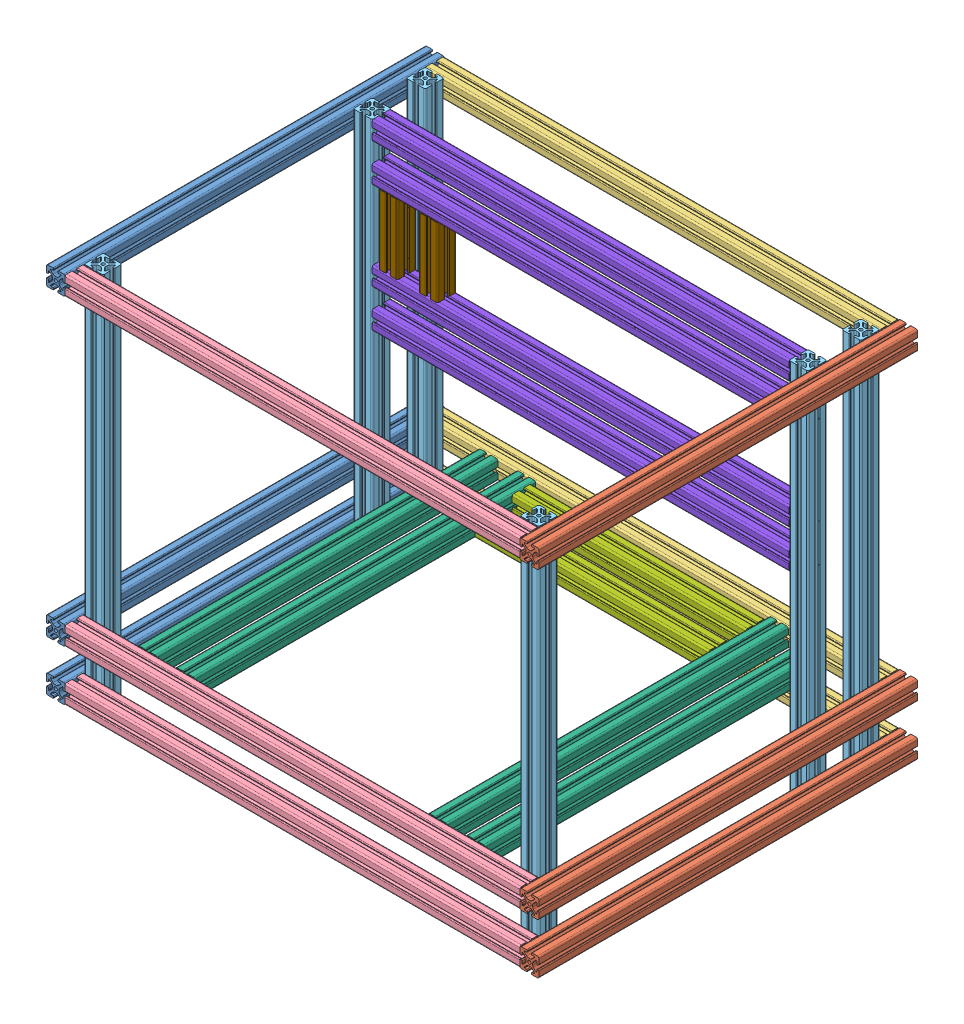
SolidWorks assembly Frame__rev6, configuration Default. Lengths in mm.
Overall size (990.6 749.3 762).
10 component instances, 10 part files, 36 mates.
Components (placement in the parent):
- Base^Frame__rev6-1: Base^Frame__rev6 [Default] at origin size (952.5 749.3 762) (hidden, virtual)
- Base_Short_Left^Frame__rev6-2: Base_Short_Left^Frame__rev6 [Default] at (0 0 381) size (38.1 749.3 762) (virtual)
- Base_Short_Right^Frame__rev6-2: Base_Short_Right^Frame__rev6 [Default] at (0 0 381) size (38.1 749.3 762) (virtual)
- Base_Long_Back^Frame__rev6-2: Base_Long_Back^Frame__rev6 [Default] at (-457.2 0 0) x (0 0 -1) z (1 0 0) size (38.1 749.3 914.4) (virtual)
- Base_Long_Front^Frame__rev6-2: Base_Long_Front^Frame__rev6 [Default] at (-457.2 0 0) x (0 0 -1) z (1 0 0) size (38.1 749.3 914.4) (virtual)
- Pillars^Frame__rev6-1: Pillars^Frame__rev6 [Default] at (0 -120.65 0) x (1 0 0) z (0 1 0) size (914.4 685.8 749.3) (virtual)
- Base Horizontals^Frame__rev6-1: Base Horizontals^Frame__rev6 [Default] at (0 0 342.9) size (698.5 38.1 685.8) (virtual)
- Base Horizontals Cross^Frame__rev6-1: Base Horizontals Cross^Frame__rev6 [Default] at (-234.95 0 0) x (0 0 -1) z (1 0 0) size (113.02 38.1 469.9) (virtual)
- Rear Horizontals^Frame__rev6-2: Rear Horizontals^Frame__rev6 [Default] at (-419.1 0 0) x (0 0 -1) z (1 0 0) size (38.1 368.3 838.2) (virtual)
- Rear Horizontals Cross^Frame__rev6-1: Rear Horizontals Cross^Frame__rev6 [Default] at (0 374.65 0) x (1 0 0) z (0 1 0) size (118.75 38.1 139.7) (virtual)
Mates (geometry in assembly coordinates):
- InPlace1: in place: plane of Base^Frame__rev6-1 through (0 0 397.75) normal (0 0 1); plane of ? through (0 0 397.75) normal (0 0 1); moOrthogonalPlaneRef_w of Base^Frame__rev6-1 through (0 0 397.75) normal (0 0 1); plane of ? through (0 0 397.75) normal (0 1 0); plane of Base^Frame__rev6-1 through (0 0 397.75) normal (0 0 1); plane of ? through (0 0 397.75) normal (1 0 0); plane of Base^Frame__rev6-1 through (0 0 381) normal (0 0 1); unknown of ?
- Coincident1: coincident aligned: plane of Base^Frame__rev6-1 through (0 0 381) normal (0 0 1); plane of Base_Short_Left^Frame__rev6-2 through (0 0 381) normal (0 0 1)
- Coincident2: coincident aligned: moOrthogonalPlaneRef_w of Base^Frame__rev6-1 through (0 0 381) axis (0 1 0); plane of Base_Short_Left^Frame__rev6-2 through (0 0 381) normal (0 1 0)
- Coincident3: coincident anti-aligned: moOrthogonalPlaneRef_w of Base^Frame__rev6-1 through (0 0 381) axis (-1 0 0); plane of Base_Short_Left^Frame__rev6-2 through (0 0 381) normal (1 0 0)
- InPlace2: in place: plane of Base^Frame__rev6-1 through (0 0 207.25) normal (0 0 1); plane of ? through (0 0 207.25) normal (0 0 1); plane of Base^Frame__rev6-1 through (0 0 207.25) normal (0 0 1); plane of ? through (0 0 207.25) normal (0 1 0); plane of Base^Frame__rev6-1 through (0 0 207.25) normal (0 0 1); plane of ? through (0 0 207.25) normal (1 0 0); plane of Base^Frame__rev6-1 through (0 0 381) normal (0 0 1); unknown of ?
- Coincident4: coincident aligned: plane of Base^Frame__rev6-1; plane of Base_Short_Right^Frame__rev6-2
- Coincident5: coincident aligned: moOrthogonalPlaneRef_w of Base^Frame__rev6-1 through (0 0 381) axis (0 1 0); plane of Base_Short_Right^Frame__rev6-2 through (0 0 381) normal (0 1 0)
- Coincident6: coincident anti-aligned: moOrthogonalPlaneRef_w of Base^Frame__rev6-1 through (0 0 381) axis (-1 0 0); plane of Base_Short_Right^Frame__rev6-2 through (0 0 381) normal (1 0 0)
- InPlace4: in place: plane of Base^Frame__rev6-1 through (-438.15 0 0) normal (1 0 0); plane of ? through (-438.15 0 0) normal (1 0 0); plane of Base^Frame__rev6-1 through (-438.15 0 0) normal (1 0 0); plane of ? through (-438.15 0 0) normal (0 1 0); plane of Base^Frame__rev6-1 through (-438.15 0 0) normal (1 0 0); plane of ? through (-438.15 0 0) normal (0 0 -1); plane of Base^Frame__rev6-1 through (-457.2 0 0) normal (1 0 0); unknown of ?
- Coincident10: coincident aligned: plane of Base^Frame__rev6-1; plane of Base_Long_Back^Frame__rev6-2
- Coincident11: coincident aligned: moOrthogonalPlaneRef_w of Base^Frame__rev6-1 through (-227.975 -457.2 0) axis (0 0 1); plane of Base_Long_Back^Frame-2 through (-457.2 0 0) normal (0 1 0)
- Coincident12: coincident anti-aligned: moOrthogonalPlaneRef_w of Base^Frame__rev6-1 through (0 0 0) axis (0 1 0); plane of Base_Long_Back^Frame-2 through (-457.2 0 0) normal (0 0 -1)
- InPlace5: in place: plane of Base^Frame__rev6-1 through (-628.65 0 0) normal (1 0 0); plane of ? through (-628.65 0 0) normal (1 0 0); plane of Base^Frame__rev6-1 through (-628.65 0 0) normal (1 0 0); plane of ? through (-628.65 0 0) normal (0 1 0); plane of Base^Frame__rev6-1 through (-628.65 0 0) normal (1 0 0); plane of ? through (-628.65 0 0) normal (0 0 -1); plane of Base^Frame__rev6-1 through (-457.2 0 0) normal (1 0 0); unknown of ?
- Coincident13: coincident aligned: plane of Base^Frame__rev6-1; plane of Base_Long_Front^Frame__rev6-2
- Coincident14: coincident aligned: moOrthogonalPlaneRef_w of Base^Frame__rev6-1 through (-227.975 -457.2 0) axis (0 0 1); plane of Base_Long_Front^Frame__rev6-2 through (-457.2 0 0) normal (0 1 0)
- Coincident15: coincident anti-aligned: moOrthogonalPlaneRef_w of Base^Frame__rev6-1 through (0 0 0) axis (0 1 0); plane of Base_Long_Front^Frame__rev6-2 through (-457.2 0 0) normal (0 0 -1)
- InPlace6: in place: plane of Base^Frame__rev6-1 through (0 -120.65 0) normal (0 1 0); plane of Pillars^Frame__rev6-1 through (0 -120.65 0) normal (0 1 0); plane of Base^Frame__rev6-1 through (0 -120.65 0) normal (0 1 0); plane of Pillars^Frame__rev6-1 through (0 -120.65 0) normal (0 0 -1); plane of Base^Frame__rev6-1 through (0 -120.65 0) normal (0 1 0); plane of Pillars^Frame__rev6-1 through (0 -120.65 0) normal (1 0 0); plane of Base^Frame__rev6-1 through (0 -120.65 0) normal (0 1 0); unknown of Pillars^Frame__rev6-1
- Coincident16: coincident aligned: plane of Base^Frame__rev6-1; plane of Pillars^Frame__rev6-1
- Coincident17: coincident aligned: moOrthogonalPlaneRef_w of Base^Frame__rev6-1; plane of Pillars^Frame__rev6-1 through (0 -120.65 0) normal (0 0 -1)
- Coincident18: coincident anti-aligned: moOrthogonalPlaneRef_w of Base^Frame__rev6-1 through (-437.525 0 -120.65) axis (0 -1 0); plane of Pillars^Frame__rev6-1 through (0 -120.65 0) normal (1 0 0)
- InPlace7: in place: plane of Base^Frame__rev6-1 through (0 0 342.9) normal (0 0 1); plane of Base Horizontals^Frame__rev6-1 through (0 0 342.9) normal (0 0 1); plane of Base^Frame__rev6-1 through (0 0 342.9) normal (0 0 1); plane of Base Horizontals^Frame__rev6-1 through (0 0 342.9) normal (0 1 0); plane of Base^Frame__rev6-1 through (0 0 342.9) normal (0 0 1); plane of Base Horizontals^Frame__rev6-1 through (0 0 342.9) normal (1 0 0); plane of Base^Frame__rev6-1 through (0 0 342.9) normal (0 0 1); unknown of Base Horizontals^Frame__rev6-1
- Coincident19: coincident aligned: plane of Base^Frame__rev6-1; plane of Base Horizontals^Frame__rev6-1
- Coincident20: coincident aligned: moOrthogonalPlaneRef_w of Base^Frame__rev6-1 through (0 0 342.9) axis (0 1 0); plane of Base Horizontals^Frame__rev6-1 through (0 0 342.9) normal (0 1 0)
- Coincident21: coincident anti-aligned: moOrthogonalPlaneRef_w of Base^Frame__rev6-1 through (0 0 342.9) axis (-1 0 0); plane of Base Horizontals^Frame__rev6-1 through (0 0 342.9) normal (1 0 0)
- InPlace9: in place: plane of Base^Frame__rev6-1 through (-247.65 0 0) normal (1 0 0); plane of ? through (-247.65 0 0) normal (1 0 0); plane of Base^Frame__rev6-1 through (-247.65 0 0) normal (1 0 0); plane of ? through (-247.65 0 0) normal (0 1 0); plane of Base^Frame__rev6-1 through (-247.65 0 0) normal (1 0 0); plane of ? through (-247.65 0 0) normal (0 0 -1); plane of Base^Frame__rev6-1 through (-234.95 0 0) normal (1 0 0); unknown of Base Horizontals Cross^Frame__rev6-1
- Coincident25: coincident aligned: plane of Base^Frame__rev6-1; plane of Base Horizontals Cross^Frame__rev6-1
- Coincident26: coincident aligned: moOrthogonalPlaneRef_w of Base^Frame__rev6-1 through (-166.37 -234.95 0) axis (0 0 1); plane of Base Horizontals Cross^Frame__rev6-1 through (-234.95 0 0) normal (0 1 0)
- Coincident27: coincident anti-aligned: moOrthogonalPlaneRef_w of Base^Frame__rev6-1 through (0 0 0) axis (0 1 0); plane of Base Horizontals Cross^Frame__rev6-1 through (-234.95 0 0) normal (0 0 -1)
- InPlace10: in place: plane of Base^Frame__rev6-1 through (-419.1 0 0) normal (1 0 0); plane of Rear Horizontals^Frame__rev6-2 through (-419.1 0 0) normal (1 0 0); plane of Base^Frame__rev6-1 through (-419.1 0 0) normal (1 0 0); plane of Rear Horizontals^Frame__rev6-2 through (-419.1 0 0) normal (0 1 0); plane of Base^Frame__rev6-1 through (-419.1 0 0) normal (1 0 0); plane of Rear Horizontals^Frame__rev6-2 through (-419.1 0 0) normal (0 0 -1); plane of Base^Frame__rev6-1 through (-419.1 0 0) normal (1 0 0); unknown of Rear Horizontals^Frame__rev6-2
- Coincident28: coincident aligned: plane of Base^Frame__rev6-1; plane of Rear Horizontals^Frame__rev6-2
- Coincident29: coincident aligned: moOrthogonalPlaneRef_w of Base^Frame__rev6-1 through (-166.37 -419.1 0) axis (0 0 1); plane of Rear Horizontals^Frame__rev6-2 through (-419.1 0 0) normal (0 1 0)
- Coincident30: coincident anti-aligned: moOrthogonalPlaneRef_w of Base^Frame__rev6-1 through (0 0 0) axis (0 1 0); plane of Rear Horizontals^Frame__rev6-2 through (-419.1 0 0) normal (0 0 -1)
- InPlace11: in place: plane of Base^Frame__rev6-1 through (0 260.35 0) normal (0 1 0); plane of ? through (0 260.35 0) normal (0 1 0); plane of Base^Frame__rev6-1 through (0 260.35 0) normal (0 1 0); plane of ? through (0 260.35 0) normal (0 0 -1); plane of Base^Frame__rev6-1 through (0 260.35 0) normal (0 1 0); plane of ? through (0 260.35 0) normal (1 0 0); plane of Base^Frame__rev6-1 through (0 374.65 0) normal (0 1 0); unknown of Rear Horizontals Cross^Frame__rev6-1
- Coincident31: coincident aligned: plane of Base^Frame__rev6-1; plane of Rear Horizontals Cross^Frame__rev6-1
- Coincident32: coincident aligned: moOrthogonalPlaneRef_w of Base^Frame__rev6-1; plane of Rear Horizontals Cross^Frame__rev6-1 through (0 374.65 0) normal (0 0 -1)
- Coincident33: coincident anti-aligned: moOrthogonalPlaneRef_w of Base^Frame__rev6-1 through (-419.1 0 374.65) axis (0 -1 0); plane of Rear Horizontals Cross^Frame__rev6-1 through (0 374.65 0) normal (1 0 0)
